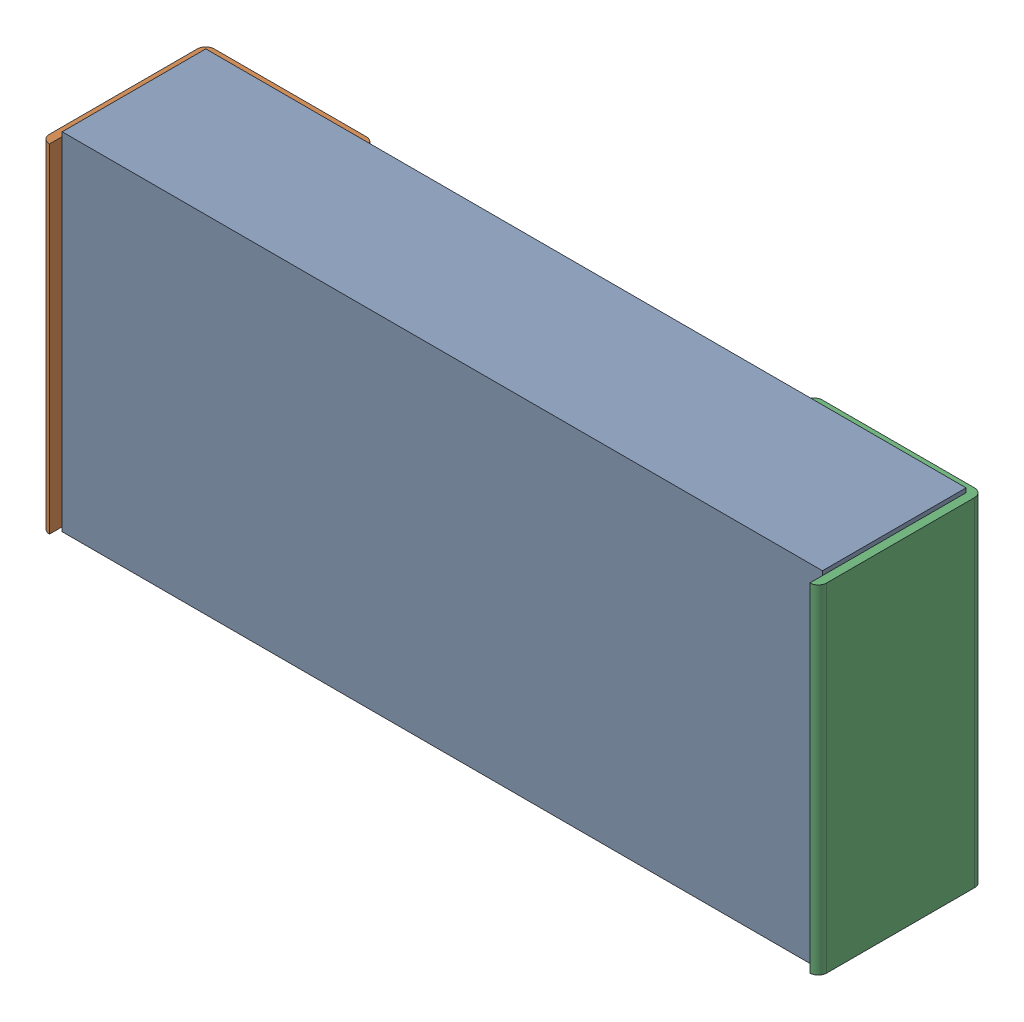
SolidWorks assembly R4, configuration Predeterminado. Lengths in mm.
Overall size (2.34 1.04 0.5).
4 component instances, 3 part files, 0 mates.
Components (placement in the parent):
- Open CASCADE STEP translator 6.8 1.13.1-1: Open CASCADE STEP translator 6.8 1.13.1 [Predeterminado] at origin size (2.34 1.04 0.5)
  - Body_1_5-1: Body_1_5 [Predeterminado] at origin size (2.29 1.04 0.43)
  - Pin_1_4-1: Pin_1_4 [Predeterminado] at (0.3048 0 0) x (-1 0 0) z (0 0 1) size (0.51 1.02 0.5)
  - Pin_2_4-1: Pin_2_4 [Predeterminado] at origin size (0.51 1.02 0.5)
